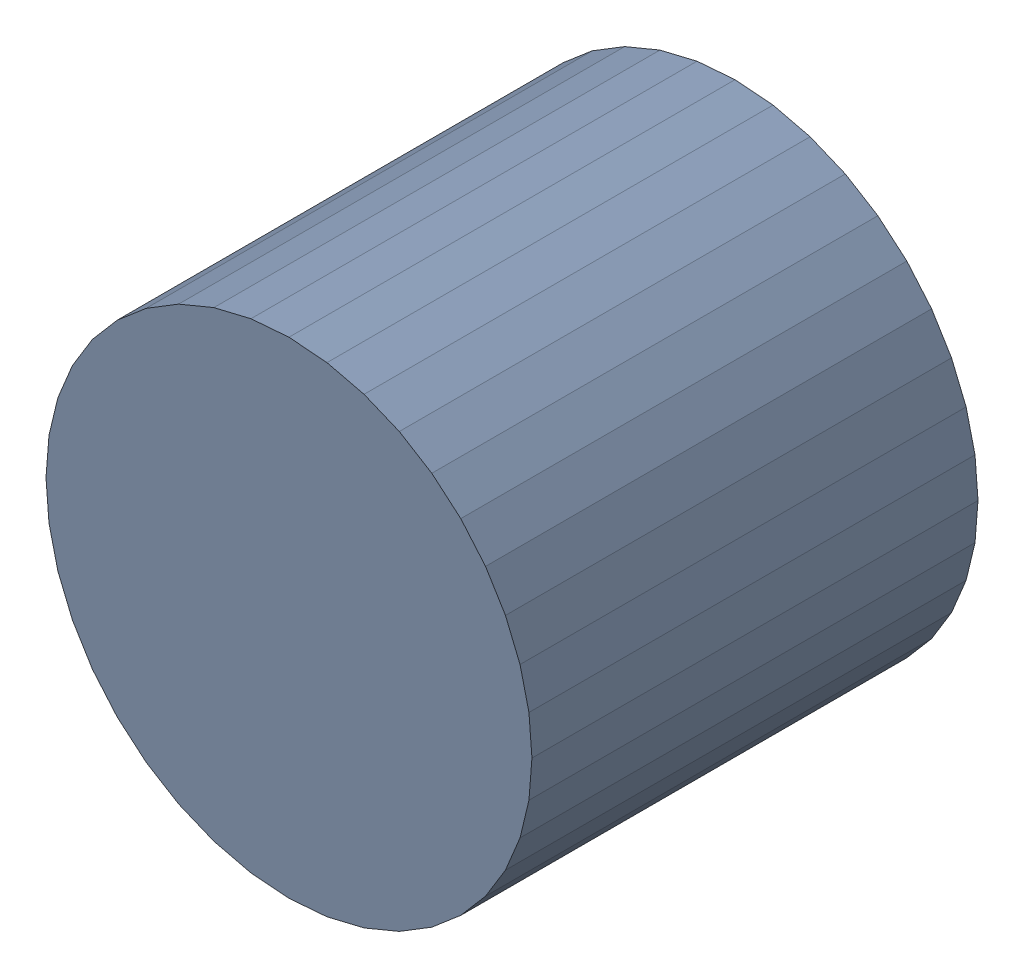
SolidWorks assembly USB67_C7, configuration Default. Lengths in mm.
Overall size (6.32 6.32 5.8).
2 component instances, 1 part files, 0 mates.
Components (placement in the parent):
- 384312384-1: 384312384 [Default] at (138.371 89.281 -6.9024) size (6.32 6.32 5.8)
  - Extruded_7-1: Extruded_7 [Default] at origin size (6.32 6.32 5.8)
